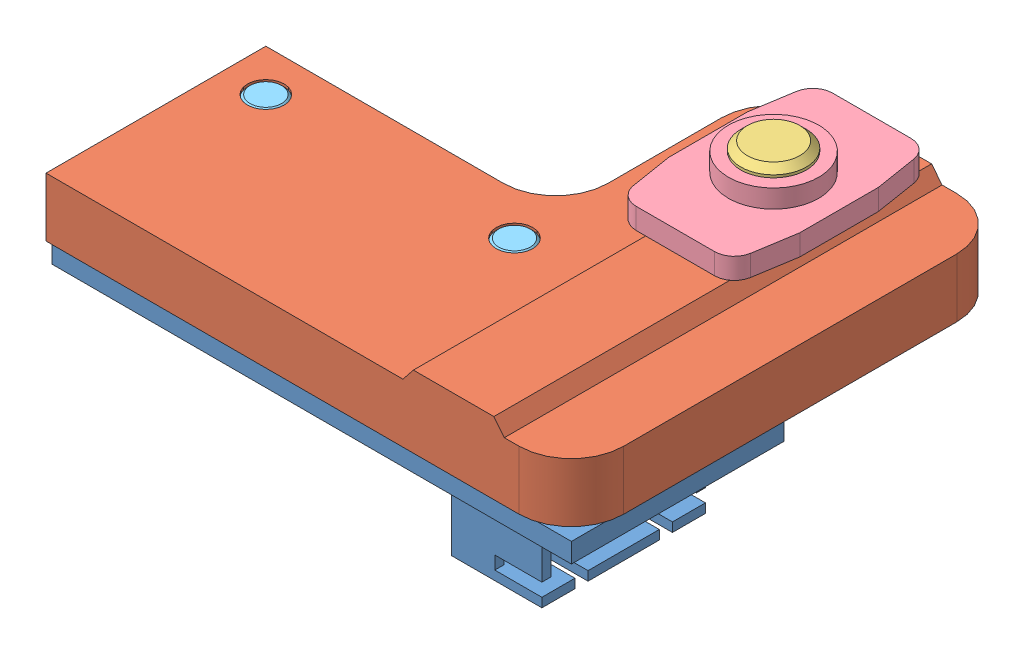
SolidWorks assembly Endstop, configuration Default. Lengths in mm.
Overall size (43.1 17.4 36.85).
7 component instances, 6 part files, 16 mates.
Components (placement in the parent):
- Bigtree-Tech_Endstop(Makerbot_Style)-1: Bigtree-Tech_Endstop(Makerbot_Style) [Default] at origin size (39.71 8.6 21.29)
- End Stop Holder V1-1: End Stop Holder V1 [Default] at (23.005 1.5 -0.525) x (1 0 0) z (0 1 0) size (43 28 6) (hidden)
- End Stop Holder V2-1: End Stop Holder V2 [Default] at (0 1.5 0) x (1 0 0) z (0 1 0) size (40.15 33.45 5.5)
- Low Profile Screw M5-1: Low Profile Screw M5 [M5 x 10] at (11.055 11.5 -16.125) x (0 1 0) z (0 0 1) size (11.5 9 9)
- Tee Nut-1: Tee Nut [Default] at (11.055 7.8 -16.125) x (0 0 -1) z (0 1 0) size (15 10 3)
- Button Head Socket Cap Screw M3-1: Button Head Socket Cap Screw M3 [M3 x 6] at (2.105 6 -5.275) x (0 1 0) z (0 0 1) size (7.65 5.7 5.7)
- Button Head Socket Cap Screw M3-2: Button Head Socket Cap Screw M3 [M3 x 6] at (-16.895 6 -5.275) x (0 1 0) z (0 0 1) size (7.65 5.7 5.7)
Mates (geometry in assembly coordinates):
- Concentric1: concentric aligned: cylinder of Bigtree-Tech_Endstop(Makerbot_Style)-1 through (-16.895 1.5 -5.275) axis (0 -1 0) radius 1.85; cylinder of End Stop Holder V1-1 through (-16.895 4.5 -5.275) axis (0 -1 0) radius 1.6
- Parallel1: parallel aligned: plane of Bigtree-Tech_Endstop(Makerbot_Style)-1 through (-19.855 1.5 -8.125) normal (0 0 -1); plane of End Stop Holder V1-1 through (-19.995 4.5 -8.525) normal (0 0 -1)
- Coincident2: coincident anti-aligned: plane of Bigtree-Tech_Endstop(Makerbot_Style)-1 through (0 1.5 0) normal (0 1 0); plane of End Stop Holder V1-1 through (23.005 1.5 -0.525) normal (0 -1 0)
- InPlace1: in place: plane of Bigtree-Tech_Endstop(Makerbot_Style)-1 through (0 1.5 0) normal (0 1 0); plane of End Stop Holder V2-1 through (0 1.5 0) normal (0 1 0); moOrthogonalPlaneRef_w of Bigtree-Tech_Endstop(Makerbot_Style)-1 through (0 1.5 0) normal (0 1 0); plane of End Stop Holder V2-1 through (0 1.5 0) normal (0 0 -1); plane of Bigtree-Tech_Endstop(Makerbot_Style)-1 through (0 1.5 0) normal (0 1 0); line of End Stop Holder V2-1 through (-55 0 1.5) axis (0 1 0); plane of Bigtree-Tech_Endstop(Makerbot_Style)-1 through (0 1.5 0) normal (0 1 0); unknown of End Stop Holder V2-1
- Coincident3: coincident aligned: plane of Bigtree-Tech_Endstop(Makerbot_Style)-1 through (0 1.5 0) normal (0 1 0); plane of End Stop Holder V2-1 through (0 1.5 0) normal (0 1 0)
- Coincident4: coincident aligned: moOrthogonalPlaneRef_w of Bigtree-Tech_Endstop(Makerbot_Style)-1 through (0 1.5 0) normal (0 0 -1); plane of End Stop Holder V2-1 through (0 1.5 0) normal (0 0 -1)
- Coincident5: coincident anti-aligned: moOrthogonalPlaneRef_w of Bigtree-Tech_Endstop(Makerbot_Style)-1 through (0 1.5 0) normal (-1 0 0); plane of End Stop Holder V2-1 through (0 1.5 0) normal (1 0 0)
- Concentric21: concentric anti-aligned: cylinder of End Stop Holder V2-1 through (11.055 6 -16.125) axis (0 -1 0) radius 2.6; cylinder of Low Profile Screw M5-1 through (11.055 1.5 -16.125) axis (0 1 0) radius 2.5
- Coincident61: coincident anti-aligned: plane of End Stop Holder V2-1 through (-1.945 1.5 -12.475) normal (0 -1 0); plane of Low Profile Screw M5-1 through (6.8936 1.5 -16.125) normal (0 1 0)
- Concentric3: concentric aligned: cylinder of Low Profile Screw M5-1 through (11.055 1.5 -16.125) axis (0 1 0) radius 2.5; cylinder of Tee Nut-1 through (11.055 10.8 -16.125) axis (0 1 0) radius 2.1
- Parallel2: parallel aligned: plane of End Stop Holder V2-1 through (20.055 6 -21.125) normal (1 0 0); plane of Tee Nut-1 through (16.055 9.4 -13.125) normal (1 0 0)
- Distance1: distance = 1.8 mm anti-aligned: plane of Tee Nut-1 through (8.055 7.8 -22.125) normal (0 -1 0); plane of End Stop Holder V2-1 through (-1.945 6 -12.475) normal (0 1 0)
- Concentric41: concentric anti-aligned: cylinder of Bigtree-Tech_Endstop(Makerbot_Style)-1 through (2.105 1.5 -5.275) axis (0 -1 0) radius 1.85; cylinder of Button Head Socket Cap Screw M3-1 through (2.105 0 -5.275) axis (0 1 0) radius 2.85
- Coincident91: coincident anti-aligned: plane of Bigtree-Tech_Endstop(Makerbot_Style)-1 through (0 0 0) normal (0 -1 0); plane of Button Head Socket Cap Screw M3-1 through (-0.745 0 -5.275) normal (0 1 0)
- Concentric51: concentric aligned: cylinder of Bigtree-Tech_Endstop(Makerbot_Style)-1 through (-16.895 1.5 -5.275) axis (0 -1 0) radius 1.85; cylinder of Button Head Socket Cap Screw M3-2 through (-16.895 0 -5.275) axis (0 -1 0) radius 2.85
- Coincident101: coincident anti-aligned: plane of Bigtree-Tech_Endstop(Makerbot_Style)-1 through (0 0 0) normal (0 -1 0); plane of Button Head Socket Cap Screw M3-2 through (-19.745 0 -5.275) normal (0 1 0)
